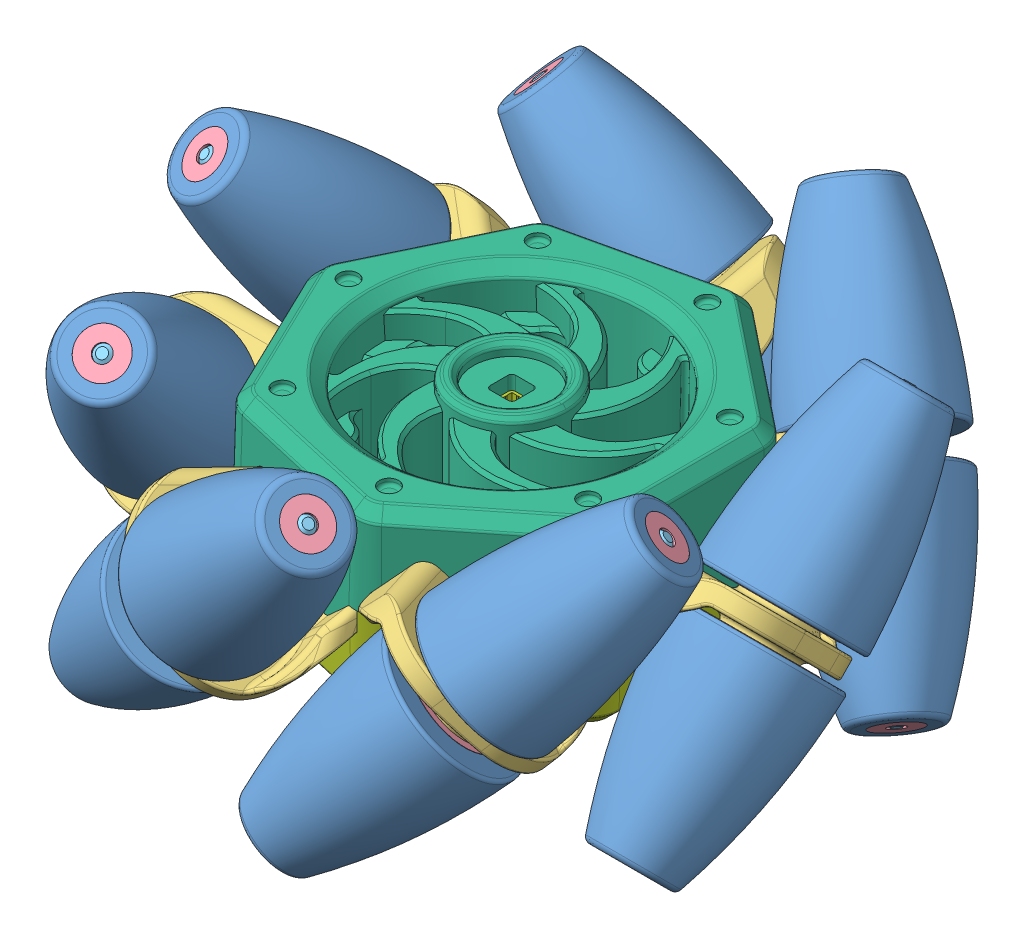
SolidWorks assembly Mecanum Left, configuration Default. Lengths in mm.
Overall size (116.24 62.26 118.47).
58 component instances, 7 part files, 0 mates.
Components (placement in the parent):
- Roller-1: Roller [Default] at (-8.8714 -0.1061 -39.3041) x (-0.709843 -0.615883 -0.341777) z (0.144671 0.347402 -0.926489) size (22.31 28.6 22.31)
- Washer-1: Washer [Default] at (-2.1949 -6.9473 -40.8283) x (-0.689398 -0.707107 0.15726) z (0.68937 -0.707107 -0.15738) size (6 6 6.25)
- Bracket Left-1: Bracket Left [Default] at origin size (28.34 25.51 28.03)
- Roller Hub-2: Roller Hub [Default] at (25.0439 -0.1061 31.5645) x (0.446415 -0.698084 -0.559815) z (0.703674 -0.112601 0.701544) size (15.2 28.65 15.2)
- Pin-1: Pin [Default] at (40.2927 0.0354 -0.0424) x (0.491193 -0.615883 -0.615969) z (0.871051 0.347402 0.34725) size (2.6 61.8 2.6)
- Roller-3: Roller [Default] at (-36.2516 0.1061 17.5878) x (-0.306866 0.707107 -0.637051) z (-0.900888 0.000087 0.434052) size (22.31 28.6 22.31)
- Washer-2: Washer [Default] at (19.6895 6.9473 -35.8342) x (-0.552772 -0.707107 -0.440957) z (0.552849 -0.707107 0.44086) size (6 6 6.25)
- Roller-5: Roller [Default] at (25.1987 -0.1061 -31.441) x (-0.175349 -0.615883 -0.768076) z (0.814571 0.347402 -0.464528) size (22.31 28.6 22.31)
- Washer-5: Washer [Default] at (-33.2899 -6.9473 -23.7392) x (-0.306866 -0.707107 0.637051) z (0.306754 -0.707107 -0.637104) size (6 6 6.25)
- Bracket Left-2: Bracket Left [Default] x (0.62347 0 -0.781847) z (0.781847 0 0.62347) size (28.34 25.51 28.03)
- Pin-2: Pin [Default] at (25.1544 0.0354 31.4763) x (0.787838 -0.615883 0) z (0.271578 0.347402 0.897528) size (2.6 61.8 2.6)
- Roller-6: Roller [Default] at (-36.3528 0.1061 -17.3777) x (0.306754 0.707107 -0.637104) z (-0.901039 0.000087 -0.433738) size (22.31 28.6 22.31)
- Washer-6: Washer [Default] at (-15.741 6.9473 -37.7357) x (-0.689398 -0.707107 0.15726) z (0.68937 -0.707107 -0.15738) size (6 6 6.25)
- Roller-9: Roller [Default] at (40.2927 -0.1061 0.099) x (0.491193 -0.615883 -0.615969) z (0.871051 0.347402 0.34725) size (22.31 28.6 22.31)
- Washer-8: Washer [Default] at (-39.3157 -6.9473 11.2269) x (0.306754 -0.707107 0.637104) z (-0.306866 -0.707107 -0.637051) size (6 6 6.25)
- Bracket Left-3: Bracket Left [Default] x (-0.22257 0 -0.974917) z (0.974917 0 -0.22257) size (28.34 25.51 28.03)
- Bracket Left-4: Bracket Left [Default] x (-0.901001 0 -0.433816) z (0.433816 0 -0.901001) size (28.34 25.51 28.03)
- Roller Hub-6: Roller Hub [Default] at (-36.2516 0.1061 17.5878) x (-0.446512 0.698084 -0.559737) z (-0.840471 -0.112601 0.530028) size (15.2 28.65 15.2)
- Roller-10: Roller [Default] at (-9.0782 0.1061 -39.2568) x (0.68937 0.707107 -0.15738) z (-0.222655 0.000087 -0.974897) size (22.31 28.6 22.31)
- Washer-10: Washer [Default] at (-39.3176 6.9473 -11.2201) x (-0.306866 -0.707107 0.637051) z (0.306754 -0.707107 -0.637104) size (6 6 6.25)
- Roller-13: Roller [Default] at (25.0439 -0.1061 31.5645) x (0.787838 -0.615883 0) z (0.271578 0.347402 0.897528) size (22.31 28.6 22.31)
- Washer-11: Washer [Default] at (-15.7344 -6.9473 37.7385) x (0.68937 -0.707107 0.15738) z (-0.689398 -0.707107 -0.15726) size (6 6 6.25)
- Bracket Left-5: Bracket Left [Default] x (-0.900926 0 0.433974) z (-0.433974 0 -0.900926) size (28.34 25.51 28.03)
- Roller Hub-8: Roller Hub [Default] at (-36.3437 -0.1061 17.3967) x (0.446512 -0.698084 0.559737) z (-0.840471 -0.112601 0.530028) size (15.2 28.65 15.2)
- Roller-14: Roller [Default] at (25.0329 0.1061 -31.5732) x (0.552849 0.707107 0.44086) z (0.623402 0.000087 -0.781901) size (22.31 28.6 22.31)
- Washer-14: Washer [Default] at (-33.2858 6.9473 23.745) x (0.306754 -0.707107 0.637104) z (-0.306866 -0.707107 -0.637051) size (6 6 6.25)
- Roller Hub-11: Roller Hub [Default] at (25.1987 -0.1061 -31.441) x (-0.645131 -0.698084 -0.310619) z (0.527331 -0.112601 -0.842166) size (15.2 28.65 15.2)
- Roller Hub-12: Roller Hub [Default] at (25.0329 0.1061 -31.5732) x (0.645131 0.698084 0.310619) z (0.527331 -0.112601 -0.842166) size (15.2 28.65 15.2)
- Pin-5: Pin [Default] at (-8.9197 0.0354 39.293) x (0.491301 -0.615883 0.615883) z (-0.532275 0.347402 0.772007) size (2.6 61.8 2.6)
- Washer-15: Washer [Default] at (19.6958 -6.9473 35.8307) x (0.552849 -0.707107 -0.44086) z (-0.552772 -0.707107 0.440957) size (6 6 6.25)
- Bracket Left-6: Bracket Left [Default] x (-0.222399 0 0.974956) z (-0.974956 0 -0.222399) size (28.34 25.51 28.03)
- Roller Hub-13: Roller Hub [Default] at (40.2927 -0.1061 0.099) x (-0.159363 -0.698084 -0.698056) z (0.98722 -0.112601 -0.112773) size (15.2 28.65 15.2)
- Roller Hub-14: Roller Hub [Default] at (-36.3528 0.1061 -17.3777) x (0.159242 0.698084 -0.698084) z (-0.938409 -0.112601 -0.326663) size (15.2 28.65 15.2)
- Roller-17: Roller [Default] at (40.2927 0.1061 -0.1131) x (0 0.707107 0.707107) z (1 0.000087 -0.000087) size (22.31 28.6 22.31)
- Washer-17: Washer [Default] at (-2.1877 6.9473 40.8287) x (0.68937 -0.707107 0.15738) z (-0.689398 -0.707107 -0.15726) size (6 6 6.25)
- Roller Hub-17: Roller Hub [Default] at (40.2927 0.1061 -0.1131) x (0.159363 0.698084 0.698056) z (0.98722 -0.112601 -0.112773) size (15.2 28.65 15.2)
- Pin-7: Pin [Default] at (-36.2823 0.0354 17.5241) x (-0.175215 -0.615883 0.768107) z (-0.935449 0.347402 0.065166) size (2.6 61.8 2.6)
- Washer-19: Washer [Default] at (40.2939 -6.9473 6.9403) x (0 -0.707107 -0.707107) z (0.000123 -0.707107 0.707107) size (6 6 6.25)
- Bracket Left-7: Bracket Left [Default] x (0.623607 0 0.781738) z (-0.781738 0 0.623607) size (28.34 25.51 28.03)
- Roller Hub-18: Roller Hub [Default] at (-36.2608 -0.1061 -17.5689) x (-0.159242 -0.698084 0.698084) z (-0.938409 -0.112601 -0.326663) size (15.2 28.65 15.2)
- Roller-20: Roller [Default] at (-9.0576 -0.1061 39.2616) x (0.491301 -0.615883 0.615883) z (-0.532275 0.347402 0.772007) size (22.31 28.6 22.31)
- Washer-20: Washer [Default] at (30.5578 6.9473 27.1659) x (0.552849 -0.707107 -0.44086) z (-0.552772 -0.707107 0.440957) size (6 6 6.25)
- Pin-9: Pin [Default] at (-36.3221 0.0354 -17.4414) x (-0.709783 -0.615883 0.341901) z (-0.634175 0.347402 -0.690749) size (2.6 61.8 2.6)
- Hub Inner Left-1: Hub Inner Left [Default] at origin size (62.26 19.81 61.13)
- Roller Hub-21: Roller Hub [Default] at (-9.0645 -0.1061 39.26) x (0.716016 -0.698084 0) z (-0.109781 -0.112601 0.987557) size (15.2 28.65 15.2)
- Roller Hub-22: Roller Hub [Default] at (-8.8577 0.1061 39.3072) x (-0.716016 0.698084 0) z (-0.109781 -0.112601 0.987557) size (15.2 28.65 15.2)
- Roller Hub-23: Roller Hub [Default] at (-9.0782 0.1061 -39.2568) x (0.645077 0.698084 -0.310732) z (-0.329669 -0.112601 -0.937358) size (15.2 28.65 15.2)
- Roller-22: Roller [Default] at (-36.3437 -0.1061 17.3967) x (-0.175215 -0.615883 0.768107) z (-0.935449 0.347402 0.065166) size (22.31 28.6 22.31)
- Washer-23: Washer [Default] at (40.2915 6.9473 -6.9544) x (0 -0.707107 -0.707107) z (0.000123 -0.707107 0.707107) size (6 6 6.25)
- Roller Hub-24: Roller Hub [Default] at (25.2097 0.1061 31.4322) x (-0.446415 0.698084 0.559815) z (0.703674 -0.112601 0.701544) size (15.2 28.65 15.2)
- Pin-11: Pin [Default] at (-9.0092 0.0354 -39.2726) x (-0.709843 -0.615883 -0.341777) z (0.144671 0.347402 -0.926489) size (2.6 61.8 2.6)
- Roller-24: Roller [Default] at (25.2152 0.1061 31.4278) x (-0.552772 0.707107 0.440957) z (0.623675 0.000087 0.781684) size (22.31 28.6 22.31)
- Roller Hub-27: Roller Hub [Default] at (-8.8714 -0.1061 -39.3041) x (-0.645077 -0.698084 0.310732) z (-0.329669 -0.112601 -0.937358) size (15.2 28.65 15.2)
- Roller-25: Roller [Default] at (-36.2608 -0.1061 -17.5689) x (-0.709783 -0.615883 0.341901) z (-0.634175 0.347402 -0.690749) size (22.31 28.6 22.31)
- Washer-26: Washer [Default] at (30.553 -6.9473 -27.1713) x (-0.552772 -0.707107 -0.440957) z (0.552849 -0.707107 0.44086) size (6 6 6.25)
- Hub Outer Left-1: Hub Outer Left [Default] at origin size (61.9 23.71 60.76)
- Pin-13: Pin [Default] at (25.0881 0.0354 -31.5291) x (-0.175349 -0.615883 -0.768076) z (0.814571 0.347402 -0.464528) size (2.6 61.8 2.6)
- Roller-28: Roller [Default] at (-8.8508 0.1061 39.3087) x (-0.689398 0.707107 -0.15726) z (-0.222314 0.000087 0.974975) size (22.31 28.6 22.31)
